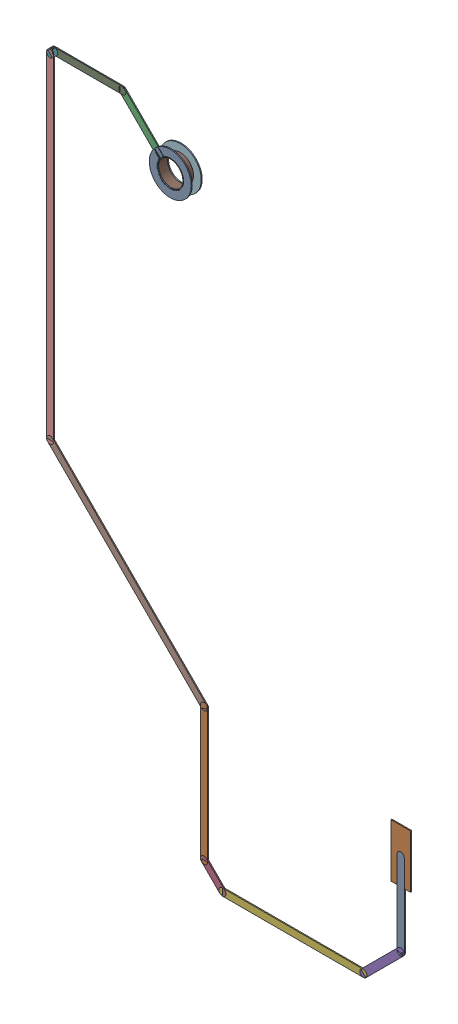
SolidWorks assembly SWDIO, configuration Predeterminado. Lengths in mm.
Overall size (13 23.26 0.39).
40 component instances, 13 part files, 0 mates.
Components (placement in the parent):
- Track (23.725mm,28.425mm)(23.725mm,31.391mm) on Top Layer-1: Track (23.725mm,28.425mm)(23.725mm,31.391mm) on Top Layer [Predeterminado] at origin size (0.25 3.22 0.04)
  - Track (23.725mm,28.425mm)(23.725mm,31.391mm) on Top Layer-1-1: Track (23.725mm,28.425mm)(23.725mm,31.391mm) on Top Layer-1 [Predeterminado] at (-68.317 -44.187 -0.0457) size (0.25 3.22 0.04)
    - Track (23.725mm,28.425mm)(23.725mm,31.391mm) on Top Layer-Part-1-1: Track (23.725mm,28.425mm)(23.725mm,31.391mm) on Top Layer-Part-1 [Predeterminado] at origin size (0.25 3.22 0.04)
- Track (16.7mm,27.749mm)(16.7mm,32.5mm) on Top Layer-1: Track (16.7mm,27.749mm)(16.7mm,32.5mm) on Top Layer [Predeterminado] at origin size (0.25 5.01 0.04)
  - Track (16.7mm,27.749mm)(16.7mm,32.5mm) on Top Layer-1-1: Track (16.7mm,27.749mm)(16.7mm,32.5mm) on Top Layer-1 [Predeterminado] at (-68.317 -44.187 -0.0457) size (0.25 5.01 0.04)
    - Track (16.7mm,27.749mm)(16.7mm,32.5mm) on Top Layer-Part-1-1: Track (16.7mm,27.749mm)(16.7mm,32.5mm) on Top Layer-Part-1 [Predeterminado] at origin size (0.25 5.01 0.04)
- Track (13.781mm,50.1mm)(15.494mm,48.387mm) on Top Layer-1: Track (13.781mm,50.1mm)(15.494mm,48.387mm) on Top Layer [Predeterminado] at origin size (1.62 1.62 0.04)
  - Track (13.781mm,50.1mm)(15.494mm,48.387mm) on Top Layer-1-1: Track (13.781mm,50.1mm)(15.494mm,48.387mm) on Top Layer-1 [Predeterminado] at (-68.317 -44.187 -0.0457) size (1.62 1.62 0.04)
    - Track (13.781mm,50.1mm)(15.494mm,48.387mm) on Top Layer-Part-1-1: Track (13.781mm,50.1mm)(15.494mm,48.387mm) on Top Layer-Part-1 [Predeterminado] at origin size (1.62 1.62 0.04)
- Track (16.7mm,27.749mm)(17.356mm,27.093mm) on Top Layer-1: Track (16.7mm,27.749mm)(17.356mm,27.093mm) on Top Layer [Predeterminado] at origin size (0.91 0.91 0.04)
  - Track (16.7mm,27.749mm)(17.356mm,27.093mm) on Top Layer-1-1: Track (16.7mm,27.749mm)(17.356mm,27.093mm) on Top Layer-1 [Predeterminado] at (-68.317 -44.187 -0.0457) size (0.91 0.91 0.04)
    - Track (16.7mm,27.749mm)(17.356mm,27.093mm) on Top Layer-Part-1-1: Track (16.7mm,27.749mm)(17.356mm,27.093mm) on Top Layer-Part-1 [Predeterminado] at origin size (0.91 0.91 0.04)
- Track (22.393mm,27.093mm)(23.725mm,28.425mm) on Top Layer-1: Track (22.393mm,27.093mm)(23.725mm,28.425mm) on Top Layer [Predeterminado] at origin size (1.59 1.59 0.04)
  - Track (22.393mm,27.093mm)(23.725mm,28.425mm) on Top Layer-1-1: Track (22.393mm,27.093mm)(23.725mm,28.425mm) on Top Layer-1 [Predeterminado] at (-68.317 -44.187 -0.0457) size (1.59 1.59 0.04)
    - Track (22.393mm,27.093mm)(23.725mm,28.425mm) on Top Layer-Part-1-1: Track (22.393mm,27.093mm)(23.725mm,28.425mm) on Top Layer-Part-1 [Predeterminado] at origin size (1.59 1.59 0.04)
- Track (17.356mm,27.093mm)(22.393mm,27.093mm) on Top Layer-1: Track (17.356mm,27.093mm)(22.393mm,27.093mm) on Top Layer [Predeterminado] at origin size (5.29 0.25 0.04)
  - Track (17.356mm,27.093mm)(22.393mm,27.093mm) on Top Layer-1-1: Track (17.356mm,27.093mm)(22.393mm,27.093mm) on Top Layer-1 [Predeterminado] at (-68.317 -44.187 -0.0457) size (5.29 0.25 0.04)
    - Track (17.356mm,27.093mm)(22.393mm,27.093mm) on Top Layer-Part-1-1: Track (17.356mm,27.093mm)(22.393mm,27.093mm) on Top Layer-Part-1 [Predeterminado] at origin size (5.29 0.25 0.04)
- Track (11.2mm,49.951mm)(11.349mm,50.1mm) on Top Layer-1: Track (11.2mm,49.951mm)(11.349mm,50.1mm) on Top Layer [Predeterminado] at origin size (0.4 0.4 0.04)
  - Track (11.2mm,49.951mm)(11.349mm,50.1mm) on Top Layer-1-1: Track (11.2mm,49.951mm)(11.349mm,50.1mm) on Top Layer-1 [Predeterminado] at (-68.317 -44.187 -0.0457) size (0.4 0.4 0.04)
    - Track (11.2mm,49.951mm)(11.349mm,50.1mm) on Top Layer-Part-1-1: Track (11.2mm,49.951mm)(11.349mm,50.1mm) on Top Layer-Part-1 [Predeterminado] at origin size (0.4 0.4 0.04)
- Track (11.2mm,38mm)(16.7mm,32.5mm) on Top Layer-1: Track (11.2mm,38mm)(16.7mm,32.5mm) on Top Layer [Predeterminado] at origin size (5.75 5.75 0.04)
  - Track (11.2mm,38mm)(16.7mm,32.5mm) on Top Layer-1-1: Track (11.2mm,38mm)(16.7mm,32.5mm) on Top Layer-1 [Predeterminado] at (-68.317 -44.187 -0.0457) size (5.75 5.75 0.04)
    - Track (11.2mm,38mm)(16.7mm,32.5mm) on Top Layer-Part-1-1: Track (11.2mm,38mm)(16.7mm,32.5mm) on Top Layer-Part-1 [Predeterminado] at origin size (5.75 5.75 0.04)
- Track (11.349mm,50.1mm)(13.781mm,50.1mm) on Top Layer-1: Track (11.349mm,50.1mm)(13.781mm,50.1mm) on Top Layer [Predeterminado] at origin size (2.69 0.25 0.04)
  - Track (11.349mm,50.1mm)(13.781mm,50.1mm) on Top Layer-1-1: Track (11.349mm,50.1mm)(13.781mm,50.1mm) on Top Layer-1 [Predeterminado] at (-68.317 -44.187 -0.0457) size (2.69 0.25 0.04)
    - Track (11.349mm,50.1mm)(13.781mm,50.1mm) on Top Layer-Part-1-1: Track (11.349mm,50.1mm)(13.781mm,50.1mm) on Top Layer-Part-1 [Predeterminado] at origin size (2.69 0.25 0.04)
- Track (11.2mm,38mm)(11.2mm,49.951mm) on Top Layer-1: Track (11.2mm,38mm)(11.2mm,49.951mm) on Top Layer [Predeterminado] at origin size (0.25 12.21 0.04)
  - Track (11.2mm,38mm)(11.2mm,49.951mm) on Top Layer-1-1: Track (11.2mm,38mm)(11.2mm,49.951mm) on Top Layer-1 [Predeterminado] at (-68.317 -44.187 -0.0457) size (0.25 12.21 0.04)
    - Track (11.2mm,38mm)(11.2mm,49.951mm) on Top Layer-Part-1-1: Track (11.2mm,38mm)(11.2mm,49.951mm) on Top Layer-Part-1 [Predeterminado] at origin size (0.25 12.21 0.04)
- Pad SWD-2(15.494mm,48.387mm) on Multi-Layer-1: Pad SWD-2(15.494mm,48.387mm) on Multi-Layer [Predeterminado] at origin size (1.5 1.5 0.39)
  - Pad Hole-1-1: Pad Hole-1 [Predeterminado] at (15.494 48.387 -0.4013) size (0.95 0.95 0.39)
    - Pad Hole-Part-1-1-1: Pad Hole-Part-1-1 [Predeterminado] at origin size (0.95 0.95 0.39)
  - Top Layer-1-1: Top Layer-1 [Predeterminado] at (15.494 48.387 -0.4013) size (1.5 1.5 0.04)
    - Top Layer-Part-1-1-1: Top Layer-Part-1-1 [Predeterminado] at origin size (1.5 1.5 0.04)
  - Top Layer-1-2: Top Layer-1 [Predeterminado] at (15.494 48.387 -0.0457) size (1.5 1.5 0.04)
    - Top Layer-Part-1-1-1: Top Layer-Part-1-1 [Predeterminado] at origin size (1.5 1.5 0.04)
- Pad RAK4600-37(23.725mm,31.391mm) on Top Layer-1: Pad RAK4600-37(23.725mm,31.391mm) on Top Layer [Predeterminado] at origin size (0.7 1.9 0.04)
  - Pad RAK4600-37(23.725mm,31.391mm) on Top Layer-1-1: Pad RAK4600-37(23.725mm,31.391mm) on Top Layer-1 [Predeterminado] at (-68.317 -44.187 -0.0457) size (0.7 1.9 0.04)
    - Pad RAK4600-37(23.725mm,31.391mm) on Top Layer-Part-1-1: Pad RAK4600-37(23.725mm,31.391mm) on Top Layer-Part-1 [Predeterminado] at origin size (0.7 1.9 0.04)
